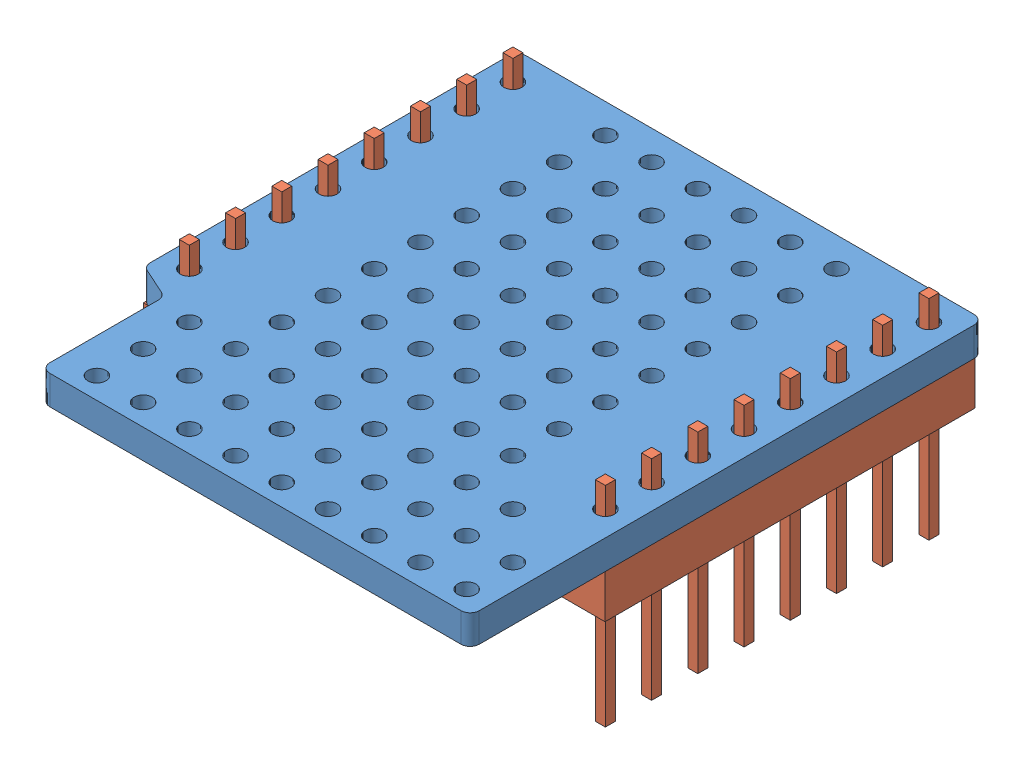
SolidWorks assembly LOLIN protoboard shield, configuration Default. Lengths in mm.
Overall size (25.6 11.5 28.2).
3 component instances, 2 part files, 6 mates.
Components (placement in the parent):
- LOLIN protoboard shield-1: LOLIN protoboard shield [Default] at origin size (25.6 1.6 28.2)
- header_m8-1: header_m8 [Default] at (-11.43 -2.5 -27.85) x (0 0 1) z (-1 0 0) size (20.32 11.5 2.5)
- header_m8-2: header_m8 [Default] at (11.43 -2.5 -27.85) x (0 0 1) z (-1 0 0) size (20.32 11.5 2.5)
Mates (geometry in assembly coordinates):
- Coincident2: coincident anti-aligned: plane of LOLIN protoboard shield-1 through (0 0 0) normal (0 -1 0); plane of header_m8-1 through (-12.68 0 -27.85) normal (0 1 0)
- Coincident3: coincident anti-aligned: plane of LOLIN protoboard shield-1 through (0 0 0) normal (0 -1 0); plane of header_m8-2 through (10.18 0 -27.85) normal (0 1 0)
- Parallel1: parallel anti-aligned: plane of header_m8-1 through (-11.43 -2.5 -27.85) normal (-1 0 0)
- Parallel2: parallel anti-aligned: plane of header_m8-2 through (11.43 -2.5 -27.85) normal (-1 0 0)
- Coincident5: coincident aligned: line of LOLIN protoboard shield-1 through (-11.43 1.6 -26.58) axis (0 -1 0); line of header_m8-1 through (-11.43 -2.5 -26.58) axis (0 -1 0)
- Coincident6: coincident aligned: line of LOLIN protoboard shield-1 through (11.43 1.6 -26.58) axis (0 -1 0); line of header_m8-2 through (11.43 -2.5 -26.58) axis (0 -1 0)
